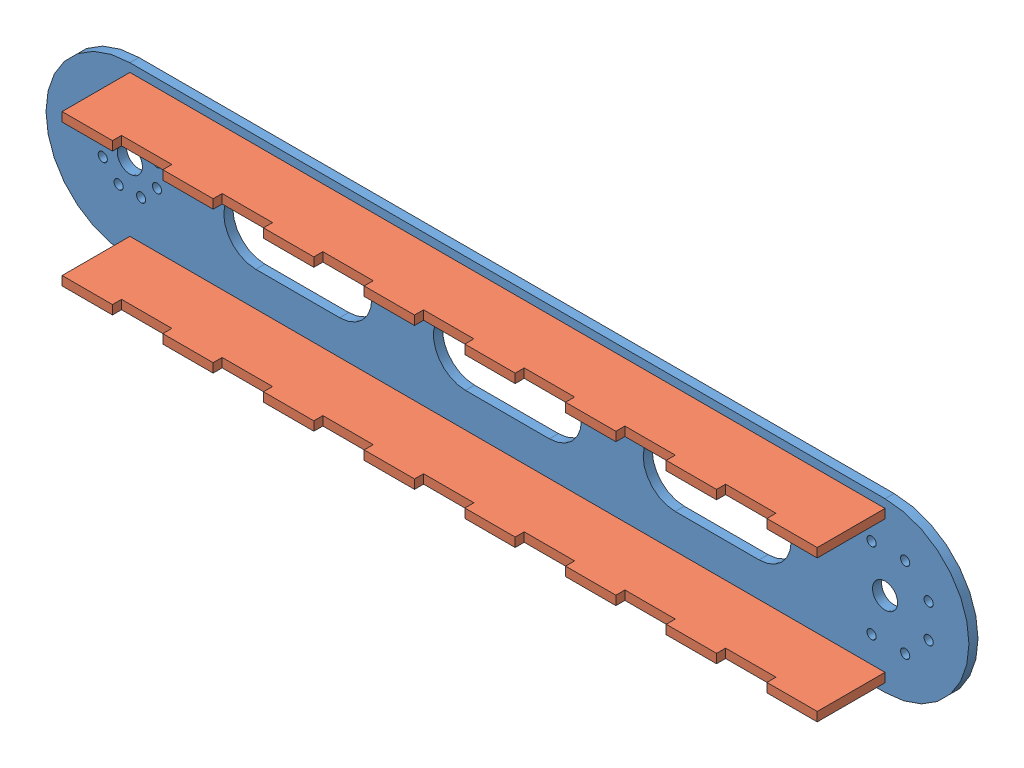
SolidWorks assembly lowerarm, configuration Default. Lengths in mm.
Overall size (550 100 45.8).
3 component instances, 2 part files, 9 mates.
Components (placement in the parent):
- ME134 Robot Lower Arm-1: ME134 Robot Lower Arm [Default] at (20.9627 0 0) size (550 100 5.4)
- ME134 Arm Flange Short-1: ME134 Arm Flange Short [Default] at (-160.6639 45 23.6543) x (1 0 0) z (0 -1 0) size (450 45.8 5.4)
- ME134 Arm Flange Short-2: ME134 Arm Flange Short [Default] at (-160.6639 -39.6 23.6543) x (1 0 0) z (0 -1 0) size (450 45.8 5.4)
Mates (geometry in assembly coordinates):
- Coincident1: coincident anti-aligned: plane of ME134 Robot Lower Arm-1 through (-272.0284 0 5.4) normal (0 0 1); plane of ME134 Arm Flange Short-1 through (-82.9912 39.6 5.4) normal (0 0 -1)
- Coincident2: coincident anti-aligned: plane of ME134 Robot Lower Arm-1 through (157.0088 45 0) normal (-1 0 0); plane of ME134 Arm Flange Short-1 through (157.0088 39.6 40.4) normal (1 0 0)
- Width1: width aligned: plane of ME134 Robot Lower Arm-1 through (127.0088 39.6 0) normal (0 1 0); plane of ME134 Arm Flange Short-1 through (127.0088 45 0) normal (0 -1 0); plane of ME134 Robot Lower Arm-1 through (-453.6551 45 23.6543) normal (0 1 0); plane of ME134 Arm Flange Short-1 through (-453.6551 39.6 23.6543) normal (0 -1 0)
- Coincident3: coincident anti-aligned: plane of ME134 Robot Lower Arm-1 through (-272.0284 0 5.4) normal (0 0 1); plane of ME134 Arm Flange Short-2 through (97.0088 -45 5.4) normal (0 0 -1)
- Coincident4: coincident anti-aligned: plane of ME134 Robot Lower Arm-1 through (157.0088 -45 0) normal (-1 0 0); plane of ME134 Arm Flange Short-2 through (157.0088 -45 40.4) normal (1 0 0)
- Width2: width anti-aligned: plane of ME134 Robot Lower Arm-1 through (127.0088 -39.6 0) normal (0 -1 0); plane of ME134 Arm Flange Short-2 through (127.0088 -45 0) normal (0 1 0); plane of ME134 Robot Lower Arm-1 through (-453.6551 -39.6 23.6543) normal (0 1 0); plane of ME134 Arm Flange Short-2 through (-453.6551 -45 23.6543) normal (0 -1 0)
- Coincident5: coincident anti-aligned: plane of ME134 Robot Lower Arm-1 through (-272.0284 0 0) normal (0 0 -1)
- Symmetric1: symmetric aligned: plane of ME134 Arm Flange Short-1 through (-453.6551 45 23.6543) normal (0 1 0); plane of ME134 Arm Flange Short-2 through (-453.6551 -45 23.6543) normal (0 -1 0)
- Coincident7: coincident anti-aligned: plane of ME134 Arm Flange Short-2 through (0 -45 5.4) normal (-1 0 0)
